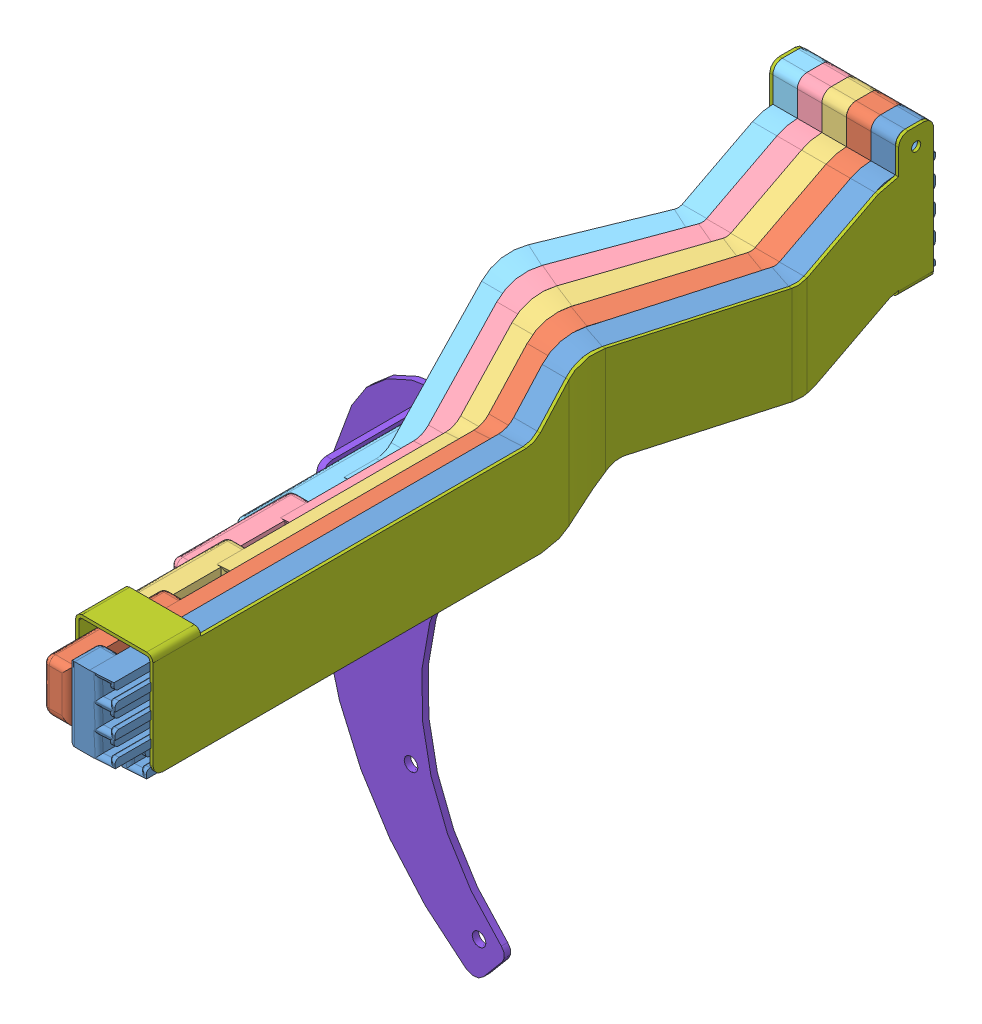
SolidWorks assembly cSL cap guides S1_S5, configuration Default. Lengths in mm.
Overall size (102.64 215.22 242.8).
34 component instances, 9 part files, 10 mates.
Components (placement in the parent):
- cSL cap guide S1-1: cSL cap guide S1 [Default] at origin size (29.52 72.96 242.8)
  - cSL cap guides-1: cSL cap guides [11] at origin size (22.91 38.83 242.8) (hidden)
  - cSL cap guides-2: cSL cap guides [12] at origin size (22.92 38.84 242.8) (hidden)
  - cSL cap guides-3: cSL cap guides [13] at origin size (22.92 38.85 242.8) (hidden)
  - cSL cap guides-4: cSL cap guides [14] at origin size (22.93 38.86 233) (hidden)
  - csl cap guide s1^cSL cap guide S1-1: csl cap guide s1^cSL cap guide S1 [Default] at (-12.5 0 0) x (0 0 -1) z (1 0 0) size (242.8 72.96 29.52) (virtual)
- cSL cap guide S2-1: cSL cap guide S2 [Default] at origin size (31.83 76.05 242.8)
  - cSL cap guides-1: cSL cap guides [21] at origin size (23.22 41.92 214.8) (hidden)
  - cSL cap guides-2: cSL cap guides [22] at origin size (23.23 41.93 214.8) (hidden)
  - cSL cap guides-3: cSL cap guides [23] at origin size (23.24 41.94 214.8) (hidden)
  - cSL cap guides-4: cSL cap guides [24] at origin size (23.24 41.95 205) (hidden)
  - cSL cap guide S2^cSL cap guide S2-1: cSL cap guide S2^cSL cap guide S2 [Default] at (-20.2 0 0) x (0 0 -1) z (1 0 0) size (242.8 76.05 31.83) (virtual)
- cSL cap guide S3-1: cSL cap guide S3 [Default] at origin size (32.15 83.17 214.8)
  - cSL cap guides-1: cSL cap guides [31] at origin size (23.53 46.05 186.8) (hidden)
  - cSL cap guides-2: cSL cap guides [32] at origin size (23.54 46.06 186.8) (hidden)
  - cSL cap guides-3: cSL cap guides [33] at origin size (23.55 46.07 186.8) (hidden)
  - cSL cap guides-4: cSL cap guides [34] at origin size (23.56 46.08 177) (hidden)
  - csl cap guide s3^cSL cap guide S3-1: csl cap guide s3^cSL cap guide S3 [Default] at (-27.9 0 0) x (0 0 -1) z (1 0 0) size (214.8 83.17 32.15) (virtual)
- cSL cap guide S4-1: cSL cap guide S4 [Default] at origin size (32.46 85.55 186.8)
  - cSL cap guides-1: cSL cap guides [41] at origin size (23.85 51.41 158.8) (hidden)
  - cSL cap guides-2: cSL cap guides [42] at origin size (23.86 51.43 158.8) (hidden)
  - cSL cap guides-3: cSL cap guides [43] at origin size (23.87 51.44 158.8) (hidden)
  - cSL cap guides-4: cSL cap guides [44] at origin size (23.88 51.45 149) (hidden)
  - cSL cap guide S4^cSL cap guide S4-1: cSL cap guide S4^cSL cap guide S4 [Default] at (-35.6 0 0) x (0 0 -1) z (1 0 0) size (186.8 85.55 32.46) (virtual)
- cSL cap guide S5-1: cSL cap guide S5 [Default] at origin size (32.76 92.52 158.8)
  - cSL cap guides-1: cSL cap guides [51] at origin size (24.17 58.37 130.8) (hidden)
  - cSL cap guides-2: cSL cap guides [52] at origin size (24.18 58.39 130.8) (hidden)
  - cSL cap guides-3: cSL cap guides [53] at origin size (24.19 58.4 130.8) (hidden)
  - cSL cap guides-4: cSL cap guides [54] at origin size (24.2 58.42 121) (hidden)
  - cSL cap guide S5^cSL cap guide S5-1: cSL cap guide S5^cSL cap guide S5 [Default] at (-43.3 0 0) x (0 0 -1) z (1 0 0) size (158.8 92.52 32.76) (virtual)
- 4-40 pan p5 MC94070A110-2: 4-40 pan p5 MC94070A110 [94070A110] at (-56.3626 76.1078 -511.2) x (0 -0.819531 -0.573035) z (-1 0 0) size (5.56 5.56 14.77)
- cSL cap guide cover-1: cSL cap guide cover [Default] at (-11.5 0 0) x (0 0 -1) z (1 0 0) size (229.93 72.49 41.29)
- cSL cap guide mount-1: cSL cap guide mount [Default] at (-0.0006 0.0001 -574.5) size (57.99 153.63 40.3)
- 4-40 pan p5 MC94070A110-3: 4-40 pan p5 MC94070A110 [94070A110] at (-58.3626 72.804 -567.5333) x (0 0 1) z (-1 0 0) size (5.56 5.56 14.77)
Mates (geometry in assembly coordinates):
- Coincident2: coincident anti-aligned: plane of cSL cap guide S5-1/cSL cap guide S5^cSL cap guide S5-1 through (-69.0626 0 0) normal (-1 0 0); plane of 4-40 pan p5 MC94070A110-2 through (-69.0626 76.1078 -511.2) normal (1 0 0)
- Concentric3: concentric anti-aligned: cylinder of cSL cap guide S5-1/cSL cap guide S5^cSL cap guide S5-1 through (-69.0626 76.1078 -511.2) axis (-1 0 0) radius 1.4732; cylinder of 4-40 pan p5 MC94070A110-2 through (-56.3626 76.1078 -511.2) axis (1 0 0) radius 2.7813
- Concentric4: concentric: cylinder of cSL cap guide S1-1/csl cap guide s1^cSL cap guide S1-1 through (-15.2 140.5 -657.9384) axis (-1 0 0) radius 1.4732; cylinder of cSL cap guide cover-1 through (-57.5602 140.5 -657.9384) axis (1 0 0) radius 1.4732
- Parallel1: parallel: line of cSL cap guide S1-1/csl cap guide s1^cSL cap guide S1-1 through (-7.5 146 -660.4384) axis (0 0 1); line of cSL cap guide cover-1 through (0.4398 146 -660.4384) axis (0 0 1)
- Coincident3: coincident anti-aligned: plane of cSL cap guide S1-1/csl cap guide s1^cSL cap guide S1-1 through (-7.5 135 -652.4384) normal (1 0 0); plane of cSL cap guide cover-1 through (-7.5 200 -646.04) normal (-1 0 0)
- Coincident4: coincident anti-aligned: plane of cSL cap guide S5-1/cSL cap guide S5^cSL cap guide S5-1 through (-69.0626 0 0) normal (-1 0 0); plane of cSL cap guide mount-1 through (-69.0626 84.4078 -572.5) normal (1 0 0)
- Distance1: distance = 0.3 mm aligned: plane of cSL cap guide S5-1/cSL cap guide S5^cSL cap guide S5-1 through (-69.0626 84.4078 -574.2) normal (0 0 -1); plane of cSL cap guide mount-1 through (-71.0626 54.4078 -574.5) normal (0 0 -1)
- Coincident7: coincident aligned: plane of cSL cap guide S5-1/cSL cap guide S5^cSL cap guide S5-1 through (-69.0626 84.4078 -574.2) normal (0 1 0); plane of cSL cap guide mount-1 through (-69.0626 84.4078 -572.5) normal (0 1 0)
- Concentric5: concentric aligned: cylinder of cSL cap guide mount-1 through (-69.0626 72.804 -567.5333) axis (1 0 0) radius 1.4732; cylinder of 4-40 pan p5 MC94070A110-3 through (-58.3626 72.804 -567.5333) axis (1 0 0) radius 2.7813
- Coincident8: coincident anti-aligned: plane of cSL cap guide mount-1 through (-71.0626 84.4078 -534.2) normal (-1 0 0); plane of 4-40 pan p5 MC94070A110-3 through (-71.0626 72.804 -567.5333) normal (1 0 0)
